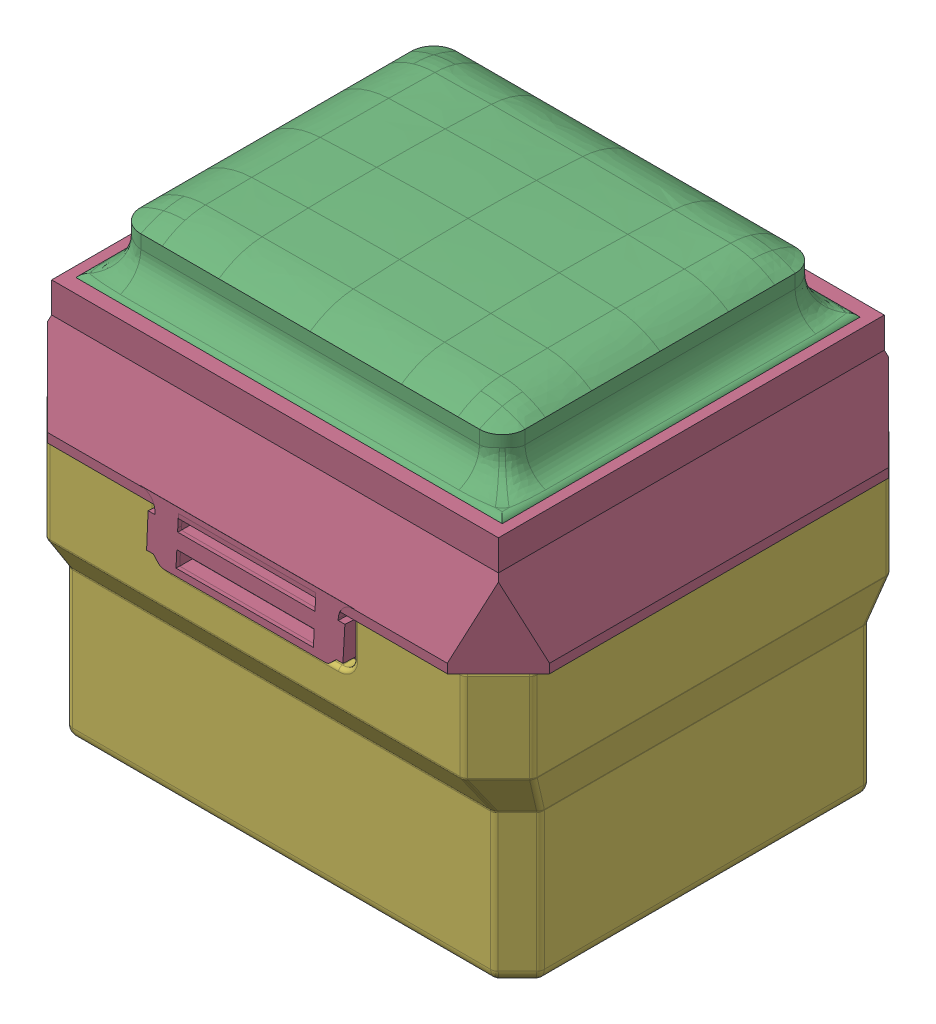
SolidWorks assembly New, configuration 默认. Lengths in mm.
Overall size (33 30.26 29.5).
6 component instances, 6 part files, 16 mates.
Components (placement in the parent):
- NewContilensall-1: NewContilensall [默认] at origin size (28.33 2.18 23.83)
- NewInsideSkin_conti-1: NewInsideSkin_conti [默认] at (0.0001 0 0.2499) size (23.8 5.48 19.29)
- NewContiTopskin-1: NewContiTopskin [默认] at (0.0001 2 0.2499) size (28.02 6.25 23.52)
- NewContiSupportBase-2: NewContiSupportBase [默认] at origin size (33 14.02 29.5)
- Newcontinuous-1: Newcontinuous [默认] at (-10.2499 23.3 7.7499) x (1 0 0) z (0 1 0) size (22 16 0.4)
- NewWholeDesignOriginal-1: NewWholeDesignOriginal [默认] at (0 0.0014 0) size (32.04 18.51 28)
Mates (geometry in assembly coordinates):
- 同心2: concentric anti-aligned: cylinder of InsideSkin_conti-1 through (10.8751 17.7531 8.6249) axis (0 1 0) radius 0.7; cylinder of Board3Con1612611OriginalSkin_TOP-1 through (10.8751 24 8.6249) axis (0 -1 0) radius 0.7
- 同心3: concentric anti-aligned: cylinder of InsideSkin_conti-1 through (10.8751 17.7531 -9.1251) axis (0 1 0) radius 0.7; cylinder of Board3Con1612611OriginalSkin_TOP-1 through (10.8751 24 -9.1251) axis (0 -1 0) radius 0.7
- 重合4: coincident aligned: plane of InsideSkin_conti-1 through (10.8751 19 -9.1251) normal (0 -1 0); plane of Board3Con1612611OriginalSkin_TOP-1 through (0.0001 19 0.2499) normal (0 -1 0)
- 重合6: coordinate: point of NewContiSupportBase-2
- 重合7: coincident anti-aligned: plane of lensall-1 through (13.75 19 -11.5) normal (0.939693 0.34202 0); plane of NewContiSupportBase-2 through (13.75 19 12.7803) normal (-0.939693 -0.34202 0)
- 同心5: concentric aligned: cylinder of lensall-1 through (13.3294 18.6938 -11.0794) axis (-0.323616 0.889126 0.323616) radius 0.5; cylinder of NewContiSupportBase-2 through (10.7866 25.6801 -8.5366) axis (-0.323616 0.889126 0.323616) radius 0.5
- 重合8: coincident anti-aligned: plane of lensall-1 through (0 18 0) normal (0 -1 0); plane of NewContiSupportBase-2 through (0 18 0) normal (0 1 0)
- 重合9: coincident anti-aligned: plane of lensall-1 through (0 19 0) normal (0 1 0); plane of Board3Con1612611OriginalSkin_TOP-1 through (0.0001 19 0.2499) normal (0 -1 0)
- 重合10: coincident anti-aligned: plane of Board3Con1612611OriginalSkin_TOP-1 through (0.0001 19 11.7499) normal (0 0 1); plane of NewContiSupportBase-2 through (-13.5999 21 11.7499) normal (0 0 -1)
- 重合11: coincident anti-aligned: plane of Board3Con1612611OriginalSkin_TOP-1 through (14.0001 19 0.2499) normal (1 0 0); plane of NewContiSupportBase-2 through (14.0001 21 11.7499) normal (-1 0 0)
- 宽度1: width aligned: plane of InsideSkin_conti-1 through (-11.3749 17.7531 -9.8251) normal (0 0 -1); plane of continuous-1 through (-11.3749 17.7531 9.3249) normal (0 0 1); plane of InsideSkin_conti-1 through (-11.2499 23.3 -8.2501) normal (0 0 -1); plane of continuous-1 through (-10.2499 23.7 7.7499) normal (0 0 1)
- 宽度2: width aligned: plane of continuous-1 through (-11.2499 23.3 -3.2352) normal (-1 0 0); plane of InsideSkin_conti-1 through (10.7501 23.7 7.7499) normal (1 0 0); plane of continuous-1 through (-12.0749 17.7531 -9.1251) normal (-1 0 0); plane of InsideSkin_conti-1 through (11.5751 17.7531 -9.1251) normal (1 0 0)
- 重合12: coincident aligned: line of InsideSkin_conti-1 through (-10.2499 23.7 -5.2501) axis (0 0 -1); line of continuous-1 through (-10.2499 23.7 -5.2501) axis (0 0 -1)
- 平行1: parallel anti-aligned: plane of NewContilensall-1 through (-1.1243 17 1.5226) normal (0 -1 0); plane of NewWholeDesignOriginal-1 through (0 -3.9986 0) normal (0 1 0)
- 宽度3: width anti-aligned: plane of NewContiSupportBase-2 through (-5.9745 12.911 -14.5571) normal (0 0.052336 -0.99863); plane of NewWholeDesignOriginal-1 through (5.9745 12.911 14.5571) normal (0 0.052336 0.99863); plane of NewContiSupportBase-2 through (-16 -4.9986 -14) normal (0 0 -1); plane of NewWholeDesignOriginal-1 through (-16 -4.9986 14) normal (0 0 1)
- 宽度4: width aligned: plane of NewContiSupportBase-2 through (-16.5 13.4 14.5) normal (-1 0 0); plane of NewWholeDesignOriginal-1 through (16.5 13.4 -14.5) normal (1 0 0); plane of NewContiSupportBase-2 through (-16 -4.9986 14) normal (-1 0 0); plane of NewWholeDesignOriginal-1 through (16 -4.9986 14) normal (1 0 0)
